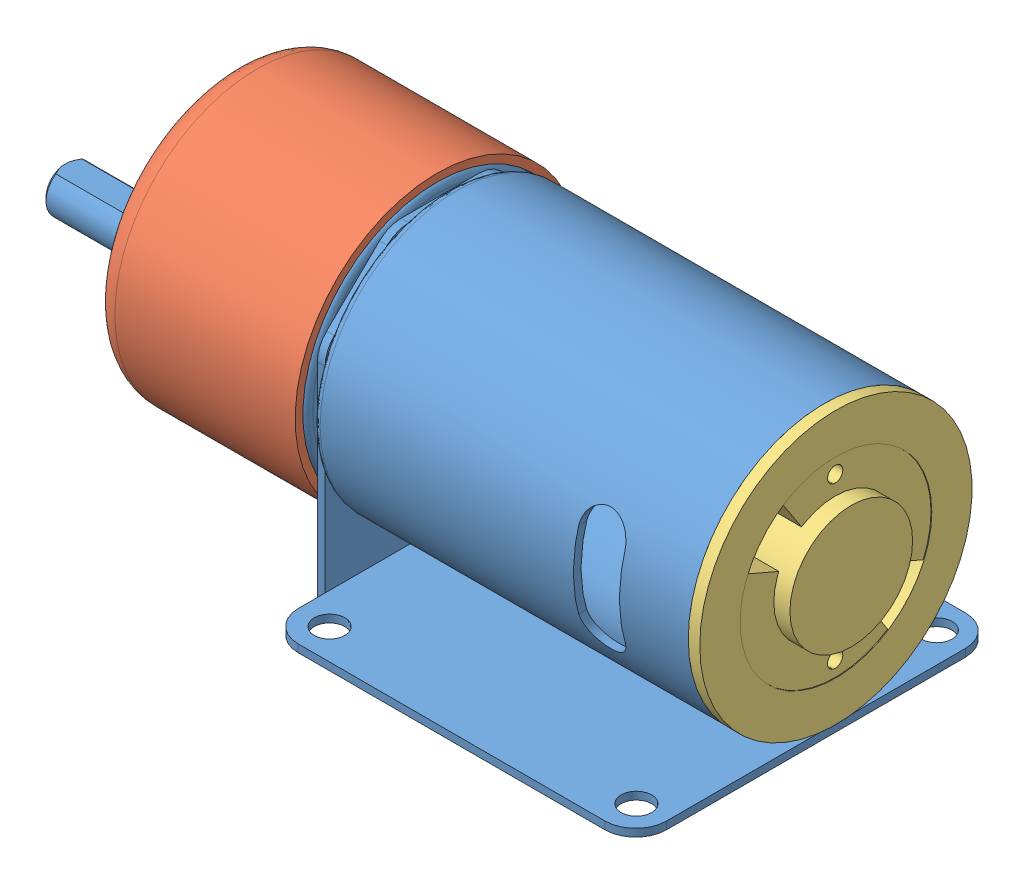
SolidWorks assembly motor, configuration Default. Lengths in mm.
Overall size (102.5 40.55 47).
3 component instances, 3 part files, 5 mates.
Components (placement in the parent):
- motor-1: motor [Default] at origin size (99 38.95 47)
- tampa1-1: tampa1 [Default] at (-51.9 21.2 0) x (0 -0.046954 -0.998897) z (1 0 0) size (37 37 26.5)
- tampa2-1: tampa2 [Default] at (20.1 21.2 0) size (8.5 35.5 35.5)
Mates (geometry in assembly coordinates):
- Concentric2: concentric aligned: circle of motor-1; circle of tampa1-1
- Concentric3: concentric anti-aligned: circle of motor-1; circle of tampa1-1
- Distance1: distance = 7 mm aligned: plane of motor-1 through (-58.9 0 0) normal (-1 0 0); plane of tampa1-1 through (-51.9 21.2 0) normal (-1 0 0)
- Concentric5: concentric: cylinder of ?; cylinder of ?
- Coincident1: coincident anti-aligned: plane of ?; plane of ?
